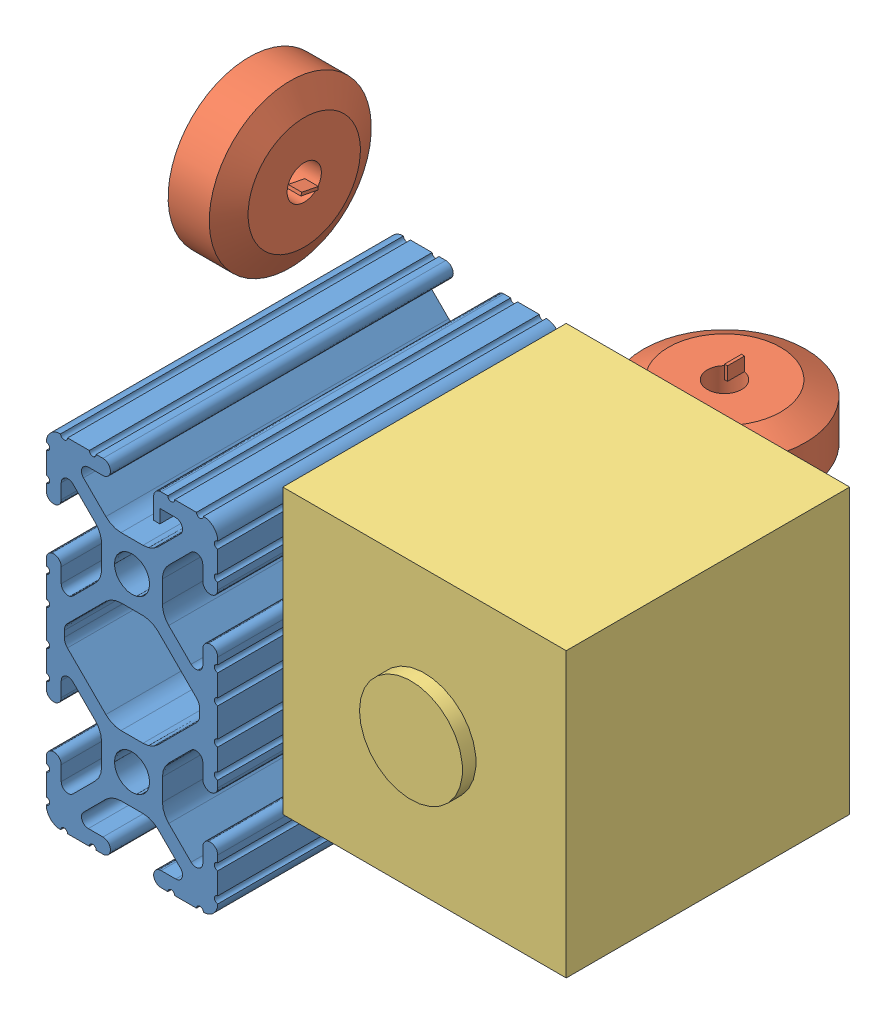
SolidWorks assembly Assem1, configuration Default. Lengths in mm.
Overall size (90.32 101.14 75.78).
4 component instances, 3 part files, 3 mates.
Components (placement in the parent):
- 1020_2_CL-1: 1020_2_CL [Default] at (-32.9095 2.3137 32.5658) size (25.4 50.8 50.8)
- bearing-1: bearing [Default] at (-8.8931 27.666 -31.2092) x (-1 0 0) z (0 0 -1) size (24 12.24 24)
- nema-1: nema [Default] at (0.7905 19.4137 -19.0728) x (0 1 0) z (1 0 0) size (42 44 42)
- bearing-2: bearing [Default] at (-49.4861 53.7654 -4.4104) x (0 -0.981715 0.190358) z (0 0.190358 0.981715) size (24 12.24 24)
Mates (geometry in assembly coordinates):
- Parallel1: parallel aligned: plane of 1020_2_CL-1 through (-20.2095 18.1633 -18.2342) normal (1 0 0); plane of bearing-2 through (-44.368 53.7654 -4.4104) normal (1 0 0)
- Coincident2: coincident aligned: plane of 1020_2_CL-1 through (-23.3591 40.4137 -18.2342) normal (0 1 0); plane of nema-1 through (21.7905 40.4137 22.9272) normal (0 1 0)
- Coincident3: coincident anti-aligned: plane of 1020_2_CL-1 through (-20.2095 -7.2367 -18.2342) normal (1 0 0); plane of nema-1 through (-20.2095 -1.5863 22.9272) normal (-1 0 0)
